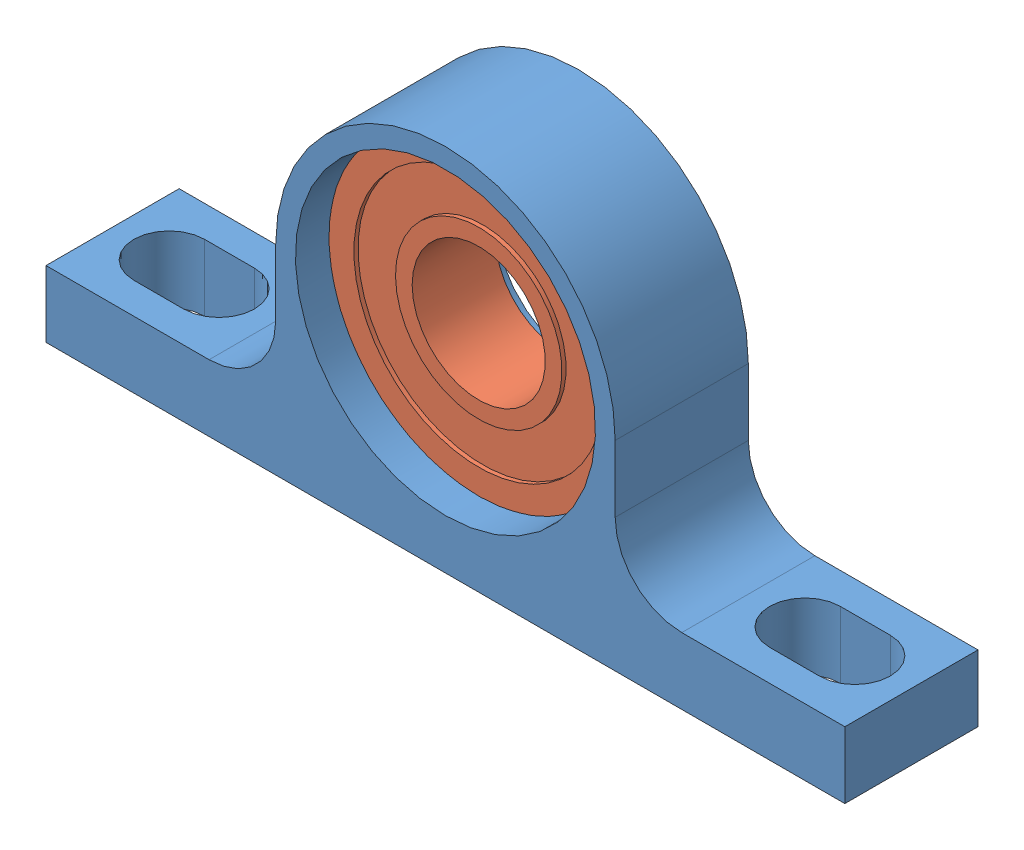
SolidWorks assembly side mount bearing block, configuration Default. Lengths in mm.
Overall size (76.2 38.21 12.7).
2 component instances, 2 part files, 0 mates.
Components (placement in the parent):
- side mount bearing block-1-1: side mount bearing block-1 [Default] at origin size (76.2 35.24 12.7)
- R8-ZZ-11-1: R8-ZZ-11 [Default] at (0 19.05 -0.7937) x (0.898829 0.4383 0) z (0 0 -1) size (28.57 28.57 7.94)
